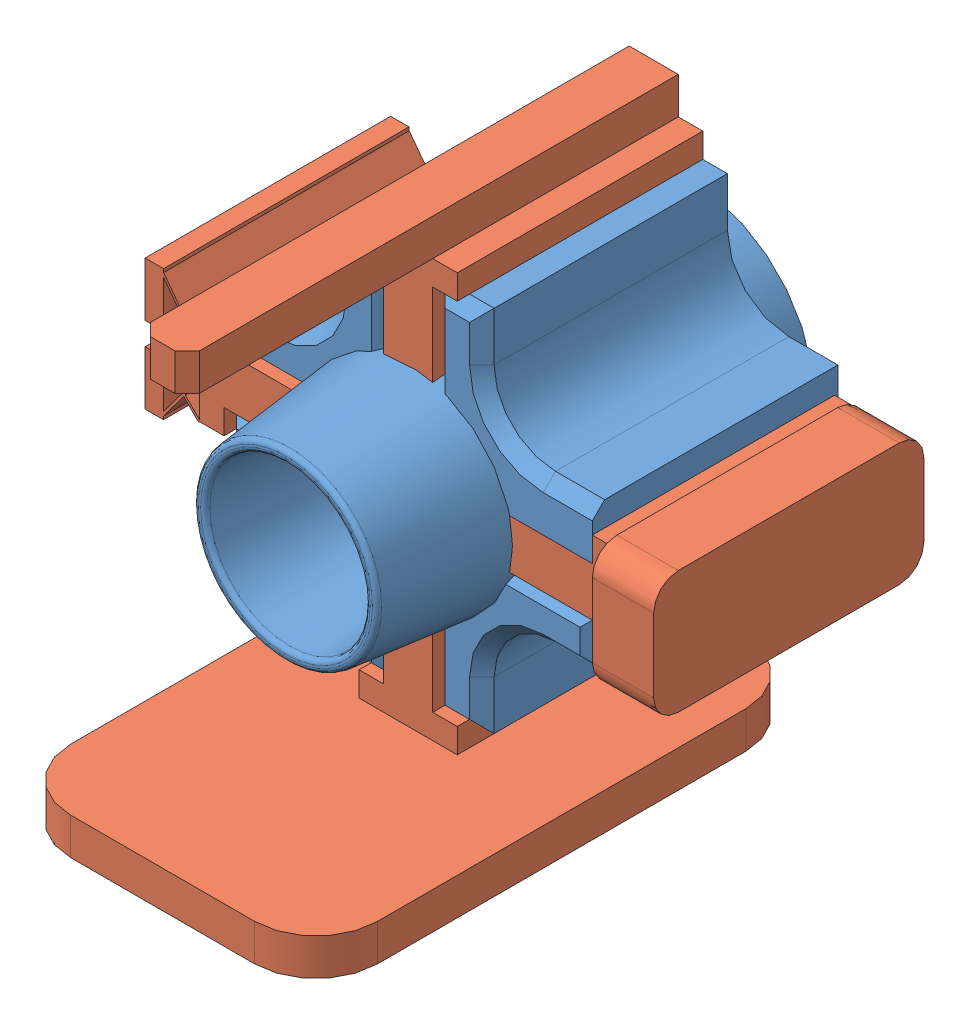
SolidWorks assembly rotate-jaw, configuration Default. Lengths in mm.
Overall size (43.43 40 43).
5 component instances, 2 part files, 15 mates.
Components (placement in the parent):
- rotate-jaw-holder-1: rotate-jaw-holder [Default] at origin size (30 30 33)
- jaw-example-1: jaw-example [jaw-examp-flex] at (-12 0 20) x (0 -1 0) z (1 0 0) size (10.66 20 13.43)
- jaw-example-2: jaw-example [jaw-examp-wide] at (0 -12 20) x (1 0 0) z (0 1 0) size (25 40 12)
- jaw-example-3: jaw-example [jaw-examp-long] at (0 12 0) x (1 0 0) z (0 -1 0) size (8 40 12)
- jaw-example-4: jaw-example [jaw-examp-standart] at (12 0 0) x (0 -1 0) z (-1 0 0) size (10 22 14)
Mates (geometry in assembly coordinates):
- Совпадение1: coincident aligned: plane of rotate-jaw-holder-1 through (0 0 0) normal (0 1 0)
- Совпадение2: coincident aligned: plane of rotate-jaw-holder-1 through (0 0 0) normal (1 0 0)
- Совпадение3: coincident aligned: plane of rotate-jaw-holder-1 through (0 0 0) normal (0 0 1)
- Совпадение4: coincident anti-aligned: plane of rotate-jaw-holder-1 through (0 8 20) normal (0 1 0); plane of jaw-example-3 through (2 8 20) normal (0 -1 0)
- Совпадение5: coincident aligned: plane of rotate-jaw-holder-1 through (0 0 20) normal (0 0 1); plane of jaw-example-3 through (0 12 20) normal (0 0 1)
- Совпадение6: coincident anti-aligned: plane of rotate-jaw-holder-1 through (2 0 20) normal (-1 0 0); plane of jaw-example-3 through (2 15 20) normal (1 0 0)
- Совпадение7: coincident aligned: plane of rotate-jaw-holder-1 through (0 0 20) normal (0 0 1); plane of jaw-example-4 through (12 0 20) normal (0 0 1)
- Совпадение8: coincident anti-aligned: plane of rotate-jaw-holder-1 through (8 0 20) normal (1 0 0); plane of jaw-example-4 through (8 -2 20) normal (-1 0 0)
- Совпадение9: coincident anti-aligned: plane of rotate-jaw-holder-1 through (0 2 20) normal (0 -1 0); plane of jaw-example-4 through (15 2 20) normal (0 1 0)
- Совпадение10: coincident aligned: plane of rotate-jaw-holder-1 through (0 0 20) normal (0 0 1); plane of jaw-example-2 through (0 -12 20) normal (0 0 1)
- Совпадение12: coincident anti-aligned: plane of rotate-jaw-holder-1 through (0 -8 20) normal (0 -1 0); plane of jaw-example-2 through (2 -8 0) normal (0 1 0)
- Совпадение13: coincident anti-aligned: plane of rotate-jaw-holder-1 through (-2 0 20) normal (1 0 0); plane of jaw-example-2 through (-2 -15 0) normal (-1 0 0)
- Совпадение14: coincident anti-aligned: plane of rotate-jaw-holder-1 through (-8 0 20) normal (-1 0 0); plane of jaw-example-1 through (-8 -2 0) normal (1 0 0)
- Совпадение15: coincident aligned: plane of rotate-jaw-holder-1 through (0 0 20) normal (0 0 1); plane of jaw-example-1 through (-12 0 20) normal (0 0 1)
- Совпадение16: coincident anti-aligned: plane of rotate-jaw-holder-1 through (0 2 20) normal (0 -1 0); plane of jaw-example-1 through (-15 2 0) normal (0 1 0)
